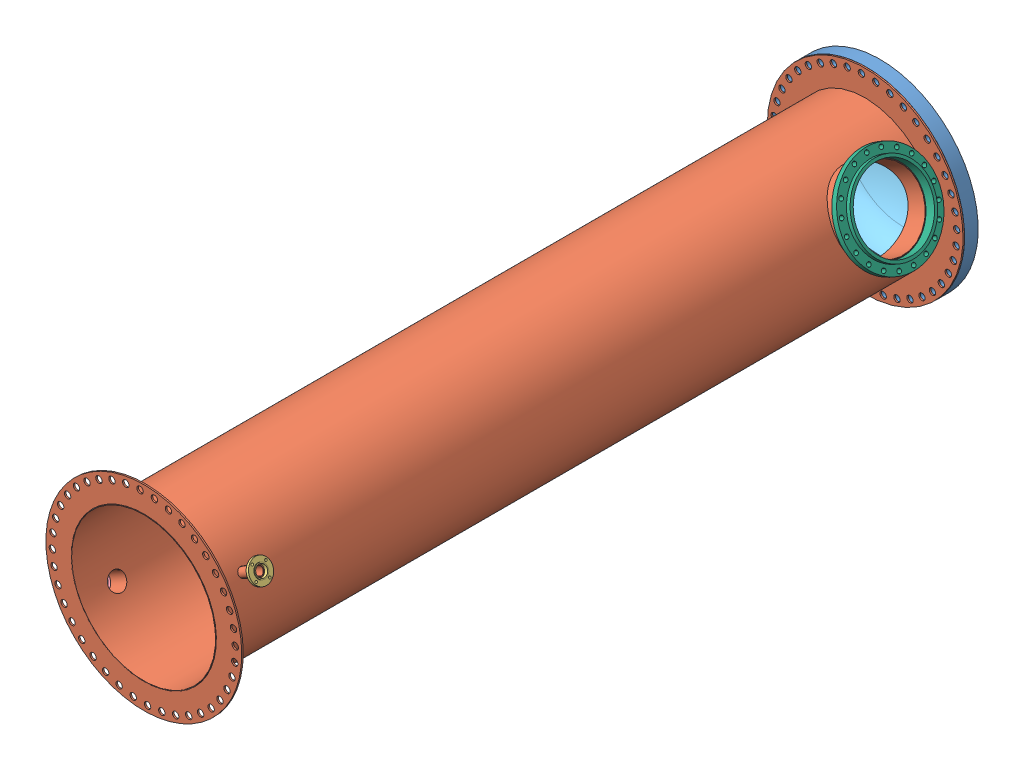
SolidWorks assembly HeatExchanger_48in_section_CDE_Assembly, configuration Default. Lengths in mm.
Overall size (2248.32 2248.32 6514.6).
8 component instances, 8 part files, 17 mates.
Components (placement in the parent):
- AWWA_C207_18 Class_F_RING_48in_Flange-1: AWWA_C207_18 Class_F_RING_48in_Flange [Default] at (-6016.7913 -1003.995 -2204.96) x (0.993275 -0.115782 0) z (0 0 1) size (1651 1651 114.3)
- Part1^HeatExchanger_48in_section_CDE_Assembly-1: Part1^HeatExchanger_48in_section_CDE_Assembly [Default] at origin (virtual)
- Part2^HeatExchanger_48in_section_CDE_Assembly-1: Part2^HeatExchanger_48in_section_CDE_Assembly [Default] at origin (virtual)
- HeatExchanger_48in_Section_CDE-1: HeatExchanger_48in_Section_CDE [Default] at (-6016.7913 -1003.995 783.5081) x (0.490162 -0.871631 0) z (0 0 1) size (1651 1651 6092.95)
- ANSIASME_4in_1250RSFO_Flange-1: ANSIASME_4in_1250RSFO_Flange [Default] at (-5343.4151 -625.5664 3642.592) x (0.401462 -0.7139 -0.573738) z (0.281225 -0.500088 0.819039) size (190.5 30.04 190.5)
- ANSIASME_6in_150RSFO_Flange-1: ANSIASME_6in_150RSFO_Flange [Default] at (-6695.3043 -1385.8021 3642.592) x (-0.487546 0.866979 0.103179) z (0.050575 -0.089934 0.994663) size (279.4 39.69 279.4)
- ASME_2-1_EllipsoidalHead_48in-3: ASME_2-1_EllipsoidalHead_48in [Default] at (-6016.7913 -1003.995 -2419.3254) size (1219.94 1219.94 307.35)
- ANSIASME_24in_150RSFO_Flange-1: ANSIASME_24in_150RSFO_Flange [Default] at (-5328.8167 -617.357 -1640.608) x (0.272458 -0.484499 -0.831281) z (0.871631 0.490162 0) size (812.8 812.8 82.61)
Mates (geometry in assembly coordinates):
- Coincident4: coincident anti-aligned: plane of AWWA_C207_18 Class_F_RING_48in_Flange-1 through (-6016.7913 -1003.995 -2145.56) normal (0 0 1); plane of HeatExchanger_48in_Section_CDE-1 through (-6018.5358 -1005.2209 -2145.56) normal (0 0 -1)
- Concentric6: concentric anti-aligned: circle of AWWA_C207_18 Class_F_RING_48in_Flange-1; circle of HeatExchanger_48in_Section_CDE-1
- Coincident5: coincident anti-aligned: circle of AWWA_C207_18 Class_F_RING_48in_Flange-1; circle of HeatExchanger_48in_Section_CDE-1
- Concentric9: concentric aligned: circle of HeatExchanger_48in_Section_CDE-1; circle of AWWA_C207_18 Class_F_RING_48in_Flange-2
- Coincident6: coincident anti-aligned: plane of HeatExchanger_48in_Section_CDE-1 through (-6016.7913 -1003.995 3947.392) normal (0 0 1); plane of AWWA_C207_18 Class_F_RING_48in_Flange-2 through (-4533.1655 -724.9775 4480.0232) normal (0.819216 0.274968 -0.503267)
- Coincident8: coincident aligned: circle of HeatExchanger_48in_Section_CDE-1; circle of AWWA_C207_18 Class_F_RING_48in_Flange-2
- Concentric10: concentric anti-aligned: circle of HeatExchanger_48in_Section_CDE-1; circle of ANSIASME_4in_1250RSFO_Flange-1
- Coincident9: coincident anti-aligned: plane of HeatExchanger_48in_Section_CDE-1 through (-5354.3528 -631.7172 3642.592) normal (0.871631 0.490162 0); plane of ANSIASME_4in_1250RSFO_Flange-1 through (-5354.3528 -631.7172 3642.592) normal (-0.871631 -0.490162 0)
- Concentric12: concentric anti-aligned: circle of HeatExchanger_48in_Section_CDE-1; circle of ANSIASME_6in_150RSFO_Flange-1
- Coincident11: coincident anti-aligned: plane of HeatExchanger_48in_Section_CDE-1 through (-6682.7187 -1378.7246 3642.592) normal (-0.871631 -0.490162 0); plane of ANSIASME_6in_150RSFO_Flange-1 through (-6682.7187 -1378.7246 3642.592) normal (0.871631 0.490162 0)
- Concentric13: concentric aligned: circle of AWWA_C207_18 Class_F_RING_48in_Flange-1; circle of ASME_2-1_EllipsoidalHead_48in-3
- Coincident12: coincident anti-aligned: plane of AWWA_C207_18 Class_F_RING_48in_Flange-1 through (-6016.7913 -1003.995 -2259.86) normal (0 0 -1); plane of ASME_2-1_EllipsoidalHead_48in-3 through (-6016.7913 -394.0273 -2259.86) normal (0 0 1)
- Concentric14: concentric anti-aligned: circle of HeatExchanger_48in_Section_CDE-1; circle of ANSIASME_24in_150RSFO_Flange-1
- Coincident13: coincident anti-aligned: plane of HeatExchanger_48in_Section_CDE-1 through (-5354.3528 -631.7172 -1640.608) normal (0.871631 0.490162 0); plane of ANSIASME_24in_150RSFO_Flange-1 through (-5354.3528 -631.7172 -1640.608) normal (-0.871631 -0.490162 0)
- Concentric19: concentric aligned: circle of HeatExchanger_48in_Section_AB-2; circle of AWWA_C207_18 Class_F_RING_48in_Flange-3
- Coincident18: coincident anti-aligned: plane of HeatExchanger_48in_Section_AB-2 through (-6016.7913 -1003.995 4061.692) normal (0 0 -1); plane of AWWA_C207_18 Class_F_RING_48in_Flange-3 through (-6016.7913 -1003.995 4061.692) normal (0 0 1)
- Coincident20: coincident aligned: circle of HeatExchanger_48in_Section_CDE-1; circle of AWWA_C207_18 Class_F_RING_48in_Flange-3
